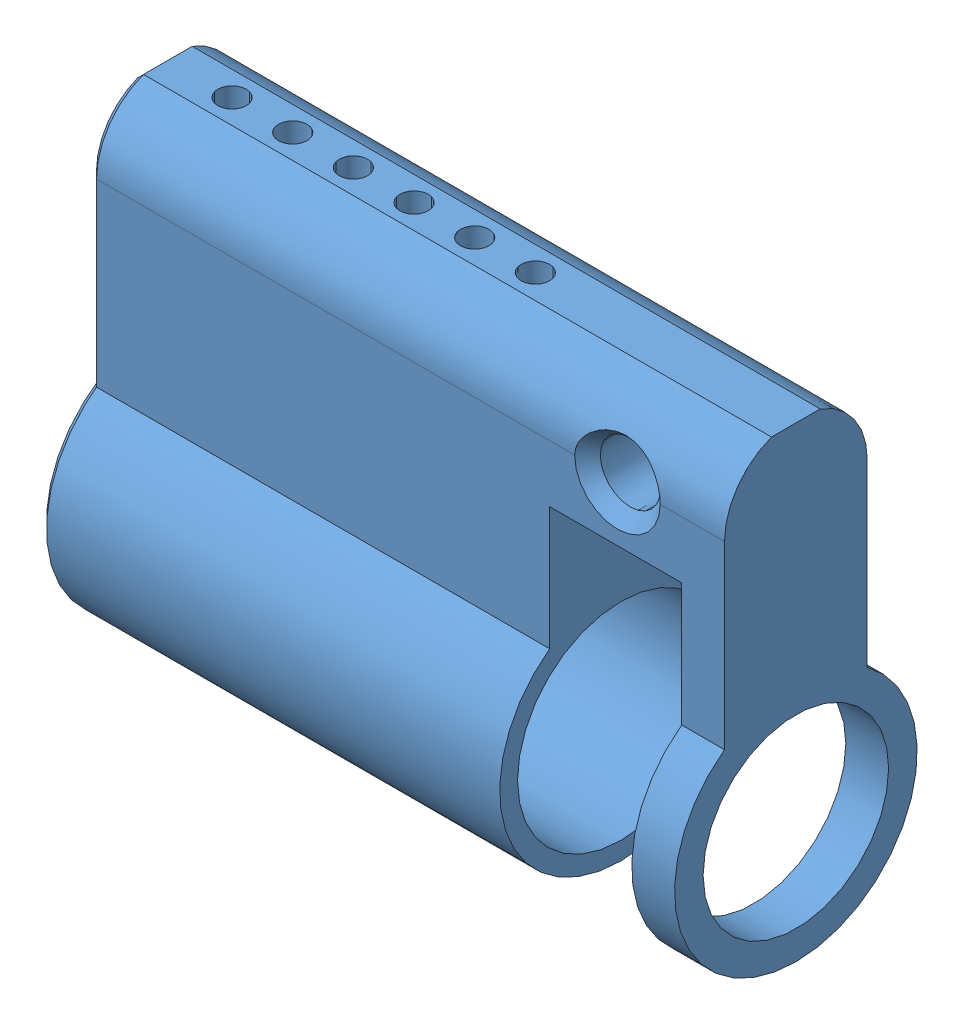
SolidWorks assembly cylinder_6-pin_sub-assembly_e, configuration Default. Lengths in mm.
Overall size (44.5 32.7 17).
7 component instances, 2 part files, 6 mates.
Components (placement in the parent):
- cylinder_d-1: cylinder_d [six-pair_of_pins] at origin size (44.5 32.7 17)
- upper_half_pin_y-1: upper_half_pin_y [cut_depth_2] at (5 15.25 0) x (0.989024 0 0.147752) z (0 -1 0) size (2 2 8)
- upper_half_pin_y-2: upper_half_pin_y [cut_depth_4] at (9.25 13.25 0) x (0.53788 0 0.843022) z (0 -1 0) size (2 2 6)
- upper_half_pin_y-3: upper_half_pin_y [cut_depth_5] at (13.5 12.25 0) x (0.923388 0 0.383868) z (0 -1 0) size (2 2 5)
- upper_half_pin_y-4: upper_half_pin_y [cut_depth_4] at (17.75 13.25 0) x (0.88402 0 0.46745) z (0 -1 0) size (2 2 6)
- upper_half_pin_y-5: upper_half_pin_y [cut_depth_1] at (22 16.4 0) x (-0.223246 0 0.974762) z (0 -1 0) size (2 2 9.15)
- upper_half_pin_y-6: upper_half_pin_y [cut_depth_3] at (26.25 14.25 0) x (-0.197827 0 0.980237) z (0 -1 0) size (2 2 7)
Mates (geometry in assembly coordinates):
- Concentric1: concentric anti-aligned: cylinder of cylinder_d-1 through (5 35 0) axis (0 -1 0) radius 1; cylinder of upper_half_pin_y-1 through (5 7.25 0) axis (0 1 0) radius 1
- Concentric2: concentric anti-aligned: cylinder of cylinder_d-1 through (9.25 35 0) axis (0 -1 0) radius 1; cylinder of upper_half_pin_y-2 through (9.25 7.25 0) axis (0 1 0) radius 1
- Concentric3: concentric anti-aligned: cylinder of cylinder_d-1 through (13.5 35 0) axis (0 -1 0) radius 1; cylinder of upper_half_pin_y-3 through (13.5 7.25 0) axis (0 1 0) radius 1
- Concentric4: concentric anti-aligned: cylinder of cylinder_d-1 through (17.75 35 0) axis (0 -1 0) radius 1; cylinder of upper_half_pin_y-4 through (17.75 7.25 0) axis (0 1 0) radius 1
- Concentric5: concentric anti-aligned: cylinder of cylinder_d-1 through (22 35 0) axis (0 -1 0) radius 1; cylinder of upper_half_pin_y-5 through (22 7.25 0) axis (0 1 0) radius 1
- Concentric6: concentric anti-aligned: cylinder of cylinder_d-1 through (26.25 35 0) axis (0 -1 0) radius 1; cylinder of upper_half_pin_y-6 through (26.25 7.25 0) axis (0 1 0) radius 1
